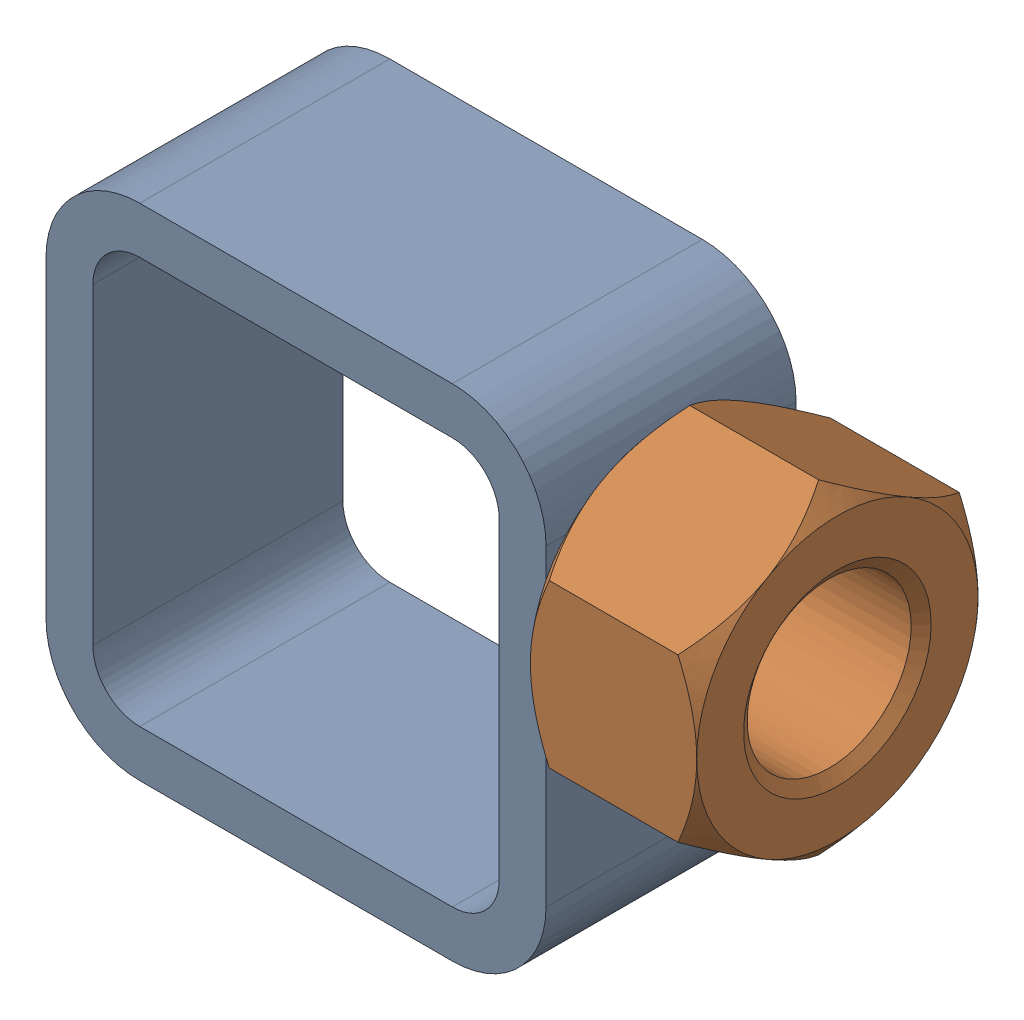
SolidWorks assembly 01-005-00-0-1, configuration Default. Lengths in mm.
Overall size (67.69 50.8 28.57).
2 component instances, 2 part files, 0 mates.
Components (placement in the parent):
- tube square_ai(PreviewCfg)-1: tube square_ai(PreviewCfg) [Default] at origin size (50.8 50.8 25.4)
- hex nut_ai(HNUT 0.7500-10-D-C)-1: hex nut_ai(HNUT 0.7500-10-D-C) [Default] at (67.691 31.75 0) x (0 0 -1) z (1 0 0) size (28.57 33 16.89)
